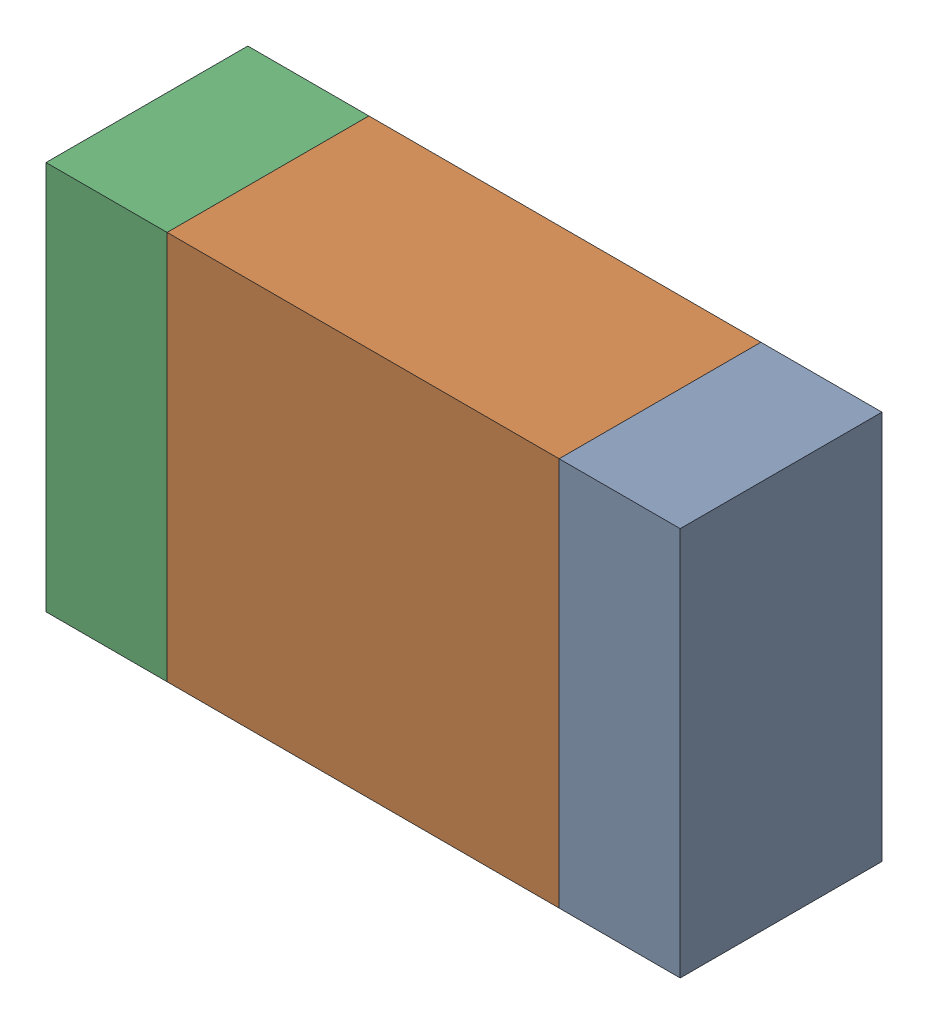
SolidWorks assembly R7-2, configuration Default. Lengths in mm.
Overall size (2.2 1.35 0.7).
6 component instances, 2 part files, 0 mates.
Components (placement in the parent):
- 959209344-2-1: 959209344-2 [Default] at (76.5821 79.5961 0) size (0.42 1.35 0.7)
  - Extruded-87-1: Extruded-87 [Default] at origin size (0.42 1.35 0.7)
- 959209480-2-1: 959209480-2 [Default] at (75.6921 79.5961 0) size (1.36 1.35 0.7)
  - Extruded-88-1: Extruded-88 [Default] at origin size (1.36 1.35 0.7)
- 959209344-2-2: 959209344-2 [Default] at (74.8021 79.5961 0) size (0.42 1.35 0.7)
  - Extruded-87-1: Extruded-87 [Default] at origin size (0.42 1.35 0.7)
